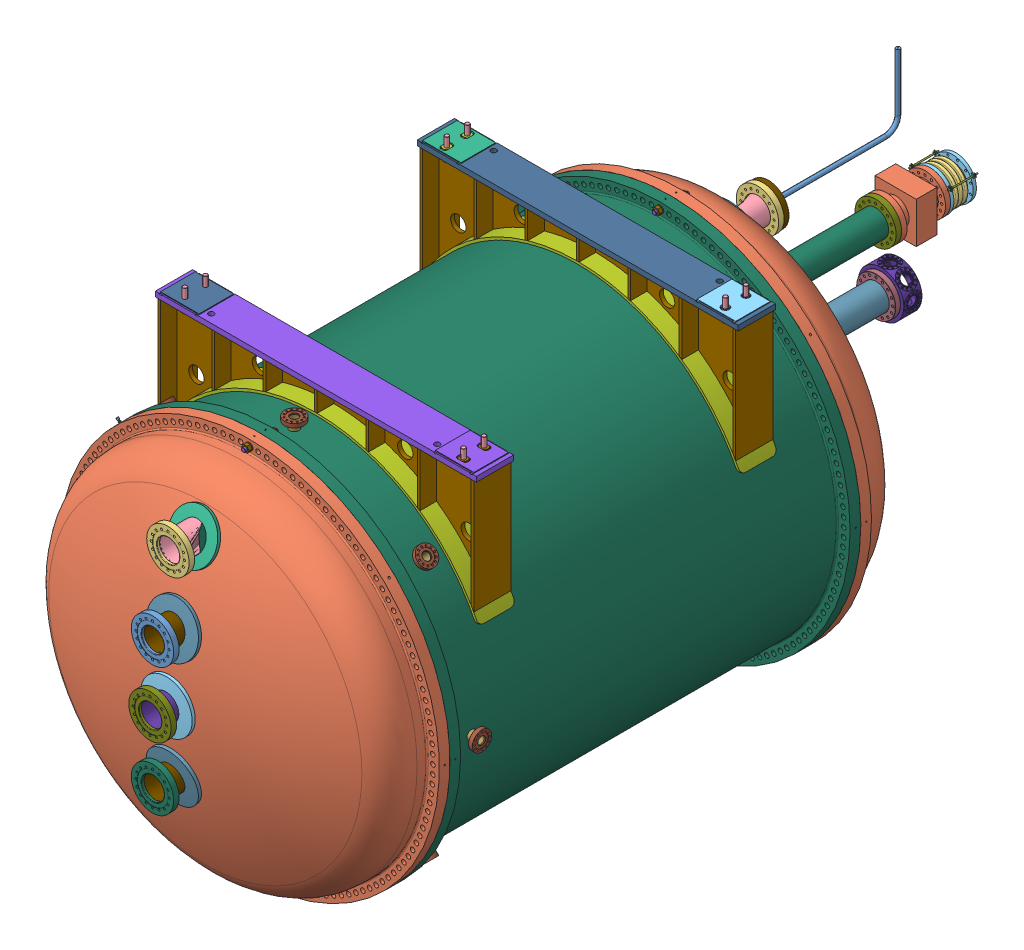
SolidWorks assembly pressure_vessel1_jordi, configuration Predeterminado. Lengths in mm.
Overall size (1480 1658.11 3261.35).
237 component instances, 64 part files, 0 mates.
Components (placement in the parent):
- mount_hardware-1: mount_hardware [Predeterminado] at (0 -3 0) size (1220 87.2 1155)
  - corner-free-1: corner-free [Predeterminado] at (-0.75 0 12.9) size (150 87 135)
    - key_free.1-1: key_free.1 [Predeterminado] at (0 0 -80) size (20 23.2 20)
    - key_free.1-2: key_free.1 [Predeterminado] at origin size (20 23.2 20)
    - fastener_set.1.1-1: fastener_set.1.1 [Predeterminado] at (0 0 -1040.4) size (50 87 50)
      - washer-1: washer [Predeterminado] at origin size (50 5 50)
      - m16-2_hhexnut-1: m16-2_hhexnut [Predeterminado] at (543.2477 766.8 336.1) size (24 16 27.71)
      - m16-stud-1: m16-stud [Predeterminado] at origin size (16 87 16)
    - fastener_set.1.1-2: fastener_set.1.1 [Predeterminado] at (0 0 -960.4) size (50 87 50)
      - washer-1: washer [Predeterminado] at origin size (50 5 50)
      - m16-2_hhexnut-1: m16-2_hhexnut [Predeterminado] at (543.2477 766.8 336.1) size (24 16 27.71)
      - m16-stud-1: m16-stud [Predeterminado] at origin size (16 87 16)
    - pad-free-1: pad-free [Predeterminado] at (1.4954 0 -288.2) x (-1 0 0) z (0 0 -1) size (150 6 135)
  - corner_hardware_long_slide-1: corner_hardware_long_slide [Predeterminado] at (0.7454 0 -275.3) x (-1 0 0) z (0 0 -1) size (150 87 135)
    - fastener_set.1.1-1: fastener_set.1.1 [Predeterminado] at (1086.4954 0 752.2) x (-1 0 0) z (0 0 -1) size (50 87 50)
      - washer-1: washer [Predeterminado] at origin size (50 5 50)
      - m16-2_hhexnut-1: m16-2_hhexnut [Predeterminado] at (543.2477 766.8 336.1) size (24 16 27.71)
      - m16-stud-1: m16-stud [Predeterminado] at origin size (16 87 16)
    - fastener_set.1.1-2: fastener_set.1.1 [Predeterminado] at (1086.4954 0 672.2) x (-1 0 0) z (0 0 -1) size (50 87 50)
      - washer-1: washer [Predeterminado] at origin size (50 5 50)
      - m16-2_hhexnut-1: m16-2_hhexnut [Predeterminado] at (543.2477 766.8 336.1) size (24 16 27.71)
      - m16-stud-1: m16-stud [Predeterminado] at origin size (16 87 16)
    - bearing_pad_1-1: bearing_pad_1 [Predeterminado] at origin size (150 6 135)
    - key.1-1: key.1 [Predeterminado] at origin size (26 23.2 30)
    - key.1-2: key.1 [Predeterminado] at (0 0 -80) size (26 23.2 30)
  - corner_hardware_transverse_slide-1: corner_hardware_transverse_slide [Predeterminado] at (-1 0 -8) size (149.75 87 135)
    - fastener_set.1.1-1: fastener_set.1.1 [Predeterminado] at (0 0 80) size (50 87 50)
      - washer-1: washer [Predeterminado] at origin size (50 5 50)
      - m16-2_hhexnut-1: m16-2_hhexnut [Predeterminado] at (543.2477 766.8 336.1) size (24 16 27.71)
      - m16-stud-1: m16-stud [Predeterminado] at origin size (16 87 16)
    - fastener_set.1.1-2: fastener_set.1.1 [Predeterminado] at origin size (50 87 50)
      - washer-1: washer [Predeterminado] at origin size (50 5 50)
      - m16-2_hhexnut-1: m16-2_hhexnut [Predeterminado] at (543.2477 766.8 336.1) size (24 16 27.71)
      - m16-stud-1: m16-stud [Predeterminado] at origin size (16 87 16)
    - bearing_pad-1: bearing_pad [Predeterminado] at origin size (149.75 6 135)
    - key-1: key [Predeterminado] at (127.1477 0 959.3477) x (0 0 -1) z (1 0 0) size (26 23.2 30)
    - key-2: key [Predeterminado] at (127.1477 0 879.3477) x (0 0 -1) z (1 0 0) size (26 23.2 30)
  - corner_fixed-1: corner_fixed [Predeterminado] at origin size (150 87 135)
    - fastener_set.1.1-1: fastener_set.1.1 [Predeterminado] at (-1085.75 0.2 72.5) size (50 87 50)
      - washer-1: washer [Predeterminado] at origin size (50 5 50)
      - m16-2_hhexnut-1: m16-2_hhexnut [Predeterminado] at (543.2477 766.8 336.1) size (24 16 27.71)
      - m16-stud-1: m16-stud [Predeterminado] at origin size (16 87 16)
    - fastener_set.1.1-2: fastener_set.1.1 [Predeterminado] at (-1085.75 0.2 -7.5) size (50 87 50)
      - washer-1: washer [Predeterminado] at origin size (50 5 50)
      - m16-2_hhexnut-1: m16-2_hhexnut [Predeterminado] at (543.2477 766.8 336.1) size (24 16 27.71)
      - m16-stud-1: m16-stud [Predeterminado] at origin size (16 87 16)
    - pad-fixed-1: pad-fixed [Predeterminado] at (-0.75 0 -7.5) size (150 6 135)
- tracking_head_assem_jordi-1: tracking_head_assem_jordi [Predeterminado] at (0 0 -17.4) x (-1 0 0) z (0 0 -1) size (1480 1510.05 550.83)
  - Hexagon_Socket_Head_Cap_Screw_5_16-18x1_255_ANSI_B18.3-1: Hexagon_Socket_Head_Cap_Screw_5_16-18x1_255_ANSI_B18.3 [Predeterminado] at (0 -660 -681.9) x (1 0 0) z (0 0 -1) size (11.91 11.91 39.8)
  - Hexagon_Socket_Head_Cap_Screw_5_16-18x1_255_ANSI_B18.3-2: Hexagon_Socket_Head_Cap_Screw_5_16-18x1_255_ANSI_B18.3 [Predeterminado] at (0 660 -681.5) x (-1 0 0) z (0 0 -1) size (11.91 11.91 39.8)
  - O-ring_press.1.1-1: O-ring_press.1.1 [Predeterminado] at (0 0 61.9) x (-1 0 0) z (0 0 -1) size (1377.4 1377.4 3.81)
  - O-ring_H2o-1: O-ring_H2o [Predeterminado] at (0 0 61.5) x (-1 0 0) z (0 0 -1) size (1392 1392 2.61)
  - head_weldment.1-1: head_weldment.1 [Predeterminado] at (0 0 -17.4) x (-1 0 0) z (0 0 -1) size (1480 1510.05 550.83)
    - reinforcement.axial.1.1.1-1: reinforcement.axial.1.1.1 [Predeterminado] at (0 -13.7355 -284.0742) x (1 0 0) z (0 0.183956 -0.982934) size (203.29 202.99 30.7)
    - nozzle_aux_l.2-1: nozzle_aux_l.2 [Predeterminado] at (0 0 -282.8) x (1 0 0) z (0 0 -1) size (165 165 21.44)
      - flange_aux_2-1: flange_aux_2 [Predeterminado] at (0 0 -69.4114) x (-1 0 0) z (0 0 -1) size (165 165 21.44)
    - nozzle_axial-1: nozzle_axial [Predeterminado] at (0 0 -282.8) x (-1 0 0) z (0 0 -1) size (165 165 85.73)
      - flange_1-1: flange_1 [Predeterminado] at (0 250 -79.4114) x (1 0 0) z (0 0 -1) size (165 165 21.44)
      - tube-1: tube [Predeterminado] at (0 0 -242.4894) size (101.6 101.6 74.63)
    - nozzle_aux_l-1: nozzle_aux_l [Predeterminado] at (0 0 -282.8) x (-1 0 0) z (0 0 -1) size (440 939.85 440)
      - nozzle_auxiliary.1-1: nozzle_auxiliary.1 [Predeterminado] at (0 -250 -242.8779) x (-1 0 0) z (0 0 1) size (440 440 440)
      - nozzle_auxiliary.1-2: nozzle_auxiliary.1 [Predeterminado] at (0 250 -242.8779) size (440 440 440)
      - flange_aux_1-1: flange_aux_1 [Predeterminado] at (0 0 -69.4114) x (-1 0 0) z (0 0 -1) size (165 165 21.44)
    - head_O_ring-1: head_O_ring [Predeterminado] at (0 0 -17.4) x (-1 0 0) z (0 0 -1) size (1480 1480 359.44)
    - nozzle_hv-1: nozzle_hv [Predeterminado] at (0 272.0886 -282.8) x (-1 0 0) z (0 0 -1) size (496.82 496.82 496.82)
      - flange_aux-1: flange_aux [Predeterminado] at (0 0 -9.4114) x (-1 0 0) z (0 0 -1) size (165 165 21.44)
      - nozzle_auxiliary-1: nozzle_auxiliary [Predeterminado] at (0 250 217.1221) size (496.82 496.82 496.82)
    - reinforcement.axial-1: reinforcement.axial [Predeterminado] at (0 0 -282.8) x (-1 0 0) z (0 0 -1) size (203.28 203.96 19.57)
    - reinforcement.axial.1.1.1-2: reinforcement.axial.1.1.1 [Predeterminado] at (0 13.7355 -284.0742) x (-1 0 0) z (0 -0.183956 -0.982934) size (203.29 202.99 30.7)
    - reinforcement.axial.1.2-1: reinforcement.axial.1.2 [Predeterminado] at (0 28.6873 -288.5308) x (-1 0 0) z (0 -0.384203 -0.923249) size (193.14 205.75 36.46)
- main_cyl_vessel-1: main_cyl_vessel [Predeterminado] at origin size (1480 1618.11 1626.05)
  - barrel_weldment.1-1: barrel_weldment.1 [Predeterminado] at origin size (1480 1537 1600)
    - support.1.1-1: support.1.1 [Predeterminado] at (0 0 882.5) size (1271.75 508.59 147.26)
      - pad-1: pad [Predeterminado] at (0 0 47.5) x (0.999999 0.001635 0) z (0 0 1) size (1271.08 410.55 147.26)
      - base_1-1: base_1 [Predeterminado] at (-0.75 27 0) size (1250 20 145)
      - plate.1-1: plate.1 [Predeterminado] at origin size (1230 442.67 145)
    - support.1-1: support.1 [Predeterminado] at (0 0 -137.5) size (1271.75 508.59 147.26)
      - base.1-1: base.1 [Predeterminado] at (0.7454 27 -1027.8) x (-1 0 0) z (0 0 -1) size (1250 20 145)
      - plate.1-1: plate.1 [Predeterminado] at origin size (1230 442.67 145)
      - pad-1: pad [Predeterminado] at (0 0 47.5) x (0.999999 0.001635 0) z (0 0 1) size (1271.08 410.55 147.26)
    - half_nipple_DN40_mdc_401002.3-1: half_nipple_DN40_mdc_401002.3 [Predeterminado] at (-504.8778 504.8778 525) x (-0.105943 -0.105943 -0.988712) z (-0.707107 0.707107 0) size (85.39 85.39 50.95)
      - flange_flat-1: flange_flat [Predeterminado] at (0 0 10.6864) x (0.988712 -0.149826 0) z (0 0 1) size (75 75 15)
      - tube_3-1: tube_3 [Predeterminado] at origin size (36 36 44.64)
    - half_nipple_DN40_mdc_401002.3-2: half_nipple_DN40_mdc_401002.3 [Predeterminado] at (-714.005 0 525) x (0 -0.149826 -0.988712) z (-1 0 0) size (85.39 85.39 50.95)
      - flange_flat-1: flange_flat [Predeterminado] at (0 0 10.6864) x (0.988712 -0.149826 0) z (0 0 1) size (75 75 15)
      - tube_3-1: tube_3 [Predeterminado] at origin size (36 36 44.64)
    - half_nipple_DN40_mdc_401002.3-3: half_nipple_DN40_mdc_401002.3 [Predeterminado] at (504.8778 -504.8778 525) x (0.105943 0.105943 -0.988712) z (0.707107 -0.707107 0) size (85.39 85.39 50.95)
      - flange_flat-1: flange_flat [Predeterminado] at (0 0 10.6864) x (0.988712 -0.149826 0) z (0 0 1) size (75 75 15)
      - tube_3-1: tube_3 [Predeterminado] at origin size (36 36 44.64)
    - half_nipple_DN40_mdc_401002.3-4: half_nipple_DN40_mdc_401002.3 [Predeterminado] at (714.005 0 525) x (0 0.149826 -0.988712) z (1 0 0) size (85.39 85.39 50.95)
      - flange_flat-1: flange_flat [Predeterminado] at (0 0 10.6864) x (0.988712 -0.149826 0) z (0 0 1) size (75 75 15)
      - tube_3-1: tube_3 [Predeterminado] at origin size (36 36 44.64)
    - half_nipple_DN40_mdc_401002.3-5: half_nipple_DN40_mdc_401002.3 [Predeterminado] at (504.8778 504.8778 525) x (-0.105943 0.105943 -0.988712) z (0.707107 0.707107 0) size (85.39 85.39 50.95)
      - flange_flat-1: flange_flat [Predeterminado] at (0 0 10.6864) x (0.988712 -0.149826 0) z (0 0 1) size (75 75 15)
      - tube_3-1: tube_3 [Predeterminado] at origin size (36 36 44.64)
    - half_nipple_DN40_mdc_401002.3-6: half_nipple_DN40_mdc_401002.3 [Predeterminado] at (0 714.005 525) x (-0.149826 0 -0.988712) z (0 1 0) size (85.39 85.39 50.95)
      - flange_flat-1: flange_flat [Predeterminado] at (0 0 10.6864) x (0.988712 -0.149826 0) z (0 0 1) size (75 75 15)
      - tube_3-1: tube_3 [Predeterminado] at origin size (36 36 44.64)
    - nozzle_DN75.1-1: nozzle_DN75.1 [Predeterminado] at (0 0 0.0857) x (0.707107 -0.707107 0) z (0 0 1) size (178.78 51.96 178.78)
      - tube_2-1: tube_2 [Predeterminado] at (0 -709.9952 516.5143) x (0.400618 0 -0.916245) z (0 -1 0) size (72 72 45.64)
      - flange_flat_DN75-1: flange_flat_DN75 [Predeterminado] at (0 -725.6914 516.5143) x (0.522753 0 -0.852484) z (0 -1 0) size (130 130 16.7)
    - nozzle_DN75.1-2: nozzle_DN75.1 [Predeterminado] at (0 0 0.0857) size (178.78 51.96 178.78)
      - tube_2-1: tube_2 [Predeterminado] at (0 -709.9952 516.5143) x (0.400618 0 -0.916245) z (0 -1 0) size (72 72 45.64)
      - flange_flat_DN75-1: flange_flat_DN75 [Predeterminado] at (0 -725.6914 516.5143) x (0.522753 0 -0.852484) z (0 -1 0) size (130 130 16.7)
    - main_vessel_bolt_flange_Oring-1: main_vessel_bolt_flange_Oring [Predeterminado] at (0 0 -140) size (1480 1480 1600)
  - half_nipple_DN40_mdc_401002.top-1: half_nipple_DN40_mdc_401002.top [Predeterminado] at (0 -729.005 516.6) x (0.400618 0 -0.916245) z (0 -1 0) size (261.68 261.68 242.65)
    - ft_CF75-1: ft_CF75 [Predeterminado] at (473.2537 -206.9251 -714.005) x (0.400618 0.916245 0) z (-0.916245 0.400618 0) size (198.72 242.65 198.72)
      - hv_feedthrough_assem-1: hv_feedthrough_assem [Predeterminado] at (45.0172 -129.75 1.9655) x (0.996195 0 0.087156) z (-0.087156 0 0.996195) size (183.43 242.65 183.43)
        - plunger-1: plunger [Predeterminado] at (0 73.6 0) size (7 109 7)
        - FT-vacom_50kV-1: FT-vacom_50kV [Predeterminado] at (-45.0172 110.4 1.9655) x (0.996195 0 -0.087156) z (0.087156 0 0.996195) size (94.08 221.5 94.08)
          - flange.1-1: flange.1 [Predeterminado] at (0 -744.3722 516.5143) x (-0.47895 0 0.877842) z (0 1 0) size (69.34 69.34 12.7)
          - insulator-1: insulator [Predeterminado] at (45.0172 -129.75 1.9655) x (0.996195 0 0.087156) z (-0.087156 0 0.996195) size (38.35 52 38.35)
          - conductor-1: conductor [Predeterminado] at (45.0172 -129.75 1.9655) x (0.996195 0 0.087156) z (-0.087156 0 0.996195) size (2 221.5 2)
        - DN75-40reducer3-1: DN75-40reducer3 [Predeterminado] at (0 -609.6136 516.5143) x (-0.222469 0 0.97494) z (0 1 0) size (130 130 19.05)
        - DN75_O-ring_adapter-1: DN75_O-ring_adapter [Predeterminado] at (0 -609.6136 516.5143) x (-0.753266 0 0.657716) z (0 -1 0) size (130 130 19.05)
  - pipe_tube5182K834-1: pipe_tube5182K834 [Predeterminado] at (-120.5041 -650.4585 -921.4) x (0.982918 -0.182173 0.026177) z (-0.182236 -0.983255 0) size (24.52 10 20.4)
    - p2_1-1: p2_1 [Predeterminado] at (-599.5111 15.6988 -1073.7738) x (-0.565333 0.04099 0.823844) z (-0.823844 0.021573 -0.566406) size (8.63 9.17 19.4)
    - p1_1-1: p1_1 [Predeterminado] at (-599.5111 15.6988 -1073.7738) x (-0.565333 0.04099 0.823844) z (-0.823844 0.021573 -0.566406) size (7.94 9.17 7.95)
  - pipe_tube5182K834-2: pipe_tube5182K834 [Predeterminado] at (-125.0832 -646.8042 679.3369) x (0.982918 -0.182173 0.026177) z (-0.182236 -0.983255 0) size (24.52 10 20.4)
    - p2_1-1: p2_1 [Predeterminado] at (-599.5111 15.6988 -1073.7738) x (-0.565333 0.04099 0.823844) z (-0.823844 0.021573 -0.566406) size (8.63 9.17 19.4)
    - p1_1-1: p1_1 [Predeterminado] at (-599.5111 15.6988 -1073.7738) x (-0.565333 0.04099 0.823844) z (-0.823844 0.021573 -0.566406) size (7.94 9.17 7.95)
  - SHOULDERBOLT_8XM6X10LG-1: SHOULDERBOLT_8XM6X10LG [Predeterminado] at (0 -670 649.6) x (0.949444 -0.313936 0) z (-0.313936 -0.949444 0) size (10 21.5 10)
- flange_bolts_16mm-1: flange_bolts_16mm [Predeterminado] at origin size (71.93 1467.41 1731.8)
  - fastener_set_16mm.2-1: fastener_set_16mm.2 [Predeterminado] at (-6.2049 -94.8144 -477.8) x (-0.998993 0.044865 0) z (0 0 -1) size (37.08 37.41 131)
    - washer_17id_28od_4t.1-1: washer_17id_28od_4t.1 [Predeterminado] at (0 -620 422.1) size (28 28 3)
    - washer_17id_28od_4t.1-2: washer_17id_28od_4t.1 [Predeterminado] at (0 -620 505.1) x (-1 0 0) z (0 0 -1) size (28 28 3)
    - stud_M16x1F.1-1: stud_M16x1F.1 [Predeterminado] at (-94.3992 -1323.6965 -306) x (-0.991122 0.132957 0) z (0 0 1) size (16 16 131)
    - nut_M16x1F.1-1: nut_M16x1F.1 [Predeterminado] at (-232.2561 -1194.854 -156.9) x (-0.927184 0.374607 0) z (0 0 1) size (25.63 27.47 13)
    - nut_M16x1F.1-2: nut_M16x1F.1 [Predeterminado] at (-379.8395 -1110.0224 1084.1) x (0.790359 -0.612644 0) z (0 0 -1) size (25.63 27.47 13)
  - fastener_set_16mm.2-2: fastener_set_16mm.2 [Predeterminado] at (0 95 -477.8) x (1 0 0) z (0 0 -1) size (37.08 37.41 131)
    - washer_17id_28od_4t.1-1: washer_17id_28od_4t.1 [Predeterminado] at (0 -620 422.1) size (28 28 3)
    - washer_17id_28od_4t.1-2: washer_17id_28od_4t.1 [Predeterminado] at (0 -620 505.1) x (-1 0 0) z (0 0 -1) size (28 28 3)
    - stud_M16x1F.1-1: stud_M16x1F.1 [Predeterminado] at (-94.3992 -1323.6965 -306) x (-0.991122 0.132957 0) z (0 0 1) size (16 16 131)
    - nut_M16x1F.1-1: nut_M16x1F.1 [Predeterminado] at (-232.2561 -1194.854 -156.9) x (-0.927184 0.374607 0) z (0 0 1) size (25.63 27.47 13)
    - nut_M16x1F.1-2: nut_M16x1F.1 [Predeterminado] at (-379.8395 -1110.0224 1084.1) x (0.790359 -0.612644 0) z (0 0 -1) size (25.63 27.47 13)
  - fastener_set_16mm.2-3: fastener_set_16mm.2 [Predeterminado] at (0 -95 -477.8) x (-1 0 0) z (0 0 -1) size (37.08 37.41 131)
    - washer_17id_28od_4t.1-1: washer_17id_28od_4t.1 [Predeterminado] at (0 -620 422.1) size (28 28 3)
    - washer_17id_28od_4t.1-2: washer_17id_28od_4t.1 [Predeterminado] at (0 -620 505.1) x (-1 0 0) z (0 0 -1) size (28 28 3)
    - stud_M16x1F.1-1: stud_M16x1F.1 [Predeterminado] at (-94.3992 -1323.6965 -306) x (-0.991122 0.132957 0) z (0 0 1) size (16 16 131)
    - nut_M16x1F.1-1: nut_M16x1F.1 [Predeterminado] at (-232.2561 -1194.854 -156.9) x (-0.927184 0.374607 0) z (0 0 1) size (25.63 27.47 13)
    - nut_M16x1F.1-2: nut_M16x1F.1 [Predeterminado] at (-379.8395 -1110.0224 1084.1) x (0.790359 -0.612644 0) z (0 0 -1) size (25.63 27.47 13)
  - fastener_set_16mm.2-4: fastener_set_16mm.2 [Predeterminado] at (0 95 195) x (-1 0 0) z (0 0 1) size (37.08 37.41 131)
    - washer_17id_28od_4t.1-1: washer_17id_28od_4t.1 [Predeterminado] at (0 -620 422.1) size (28 28 3)
    - washer_17id_28od_4t.1-2: washer_17id_28od_4t.1 [Predeterminado] at (0 -620 505.1) x (-1 0 0) z (0 0 -1) size (28 28 3)
    - stud_M16x1F.1-1: stud_M16x1F.1 [Predeterminado] at (-94.3992 -1323.6965 -306) x (-0.991122 0.132957 0) z (0 0 1) size (16 16 131)
    - nut_M16x1F.1-1: nut_M16x1F.1 [Predeterminado] at (-232.2561 -1194.854 -156.9) x (-0.927184 0.374607 0) z (0 0 1) size (25.63 27.47 13)
    - nut_M16x1F.1-2: nut_M16x1F.1 [Predeterminado] at (-379.8395 -1110.0224 1084.1) x (0.790359 -0.612644 0) z (0 0 -1) size (25.63 27.47 13)
  - fastener_set_16mm.2-5: fastener_set_16mm.2 [Predeterminado] at (0 -95 195) size (37.08 37.41 131)
    - washer_17id_28od_4t.1-1: washer_17id_28od_4t.1 [Predeterminado] at (0 -620 422.1) size (28 28 3)
    - washer_17id_28od_4t.1-2: washer_17id_28od_4t.1 [Predeterminado] at (0 -620 505.1) x (-1 0 0) z (0 0 -1) size (28 28 3)
    - stud_M16x1F.1-1: stud_M16x1F.1 [Predeterminado] at (-94.3992 -1323.6965 -306) x (-0.991122 0.132957 0) z (0 0 1) size (16 16 131)
    - nut_M16x1F.1-1: nut_M16x1F.1 [Predeterminado] at (-232.2561 -1194.854 -156.9) x (-0.927184 0.374607 0) z (0 0 1) size (25.63 27.47 13)
    - nut_M16x1F.1-2: nut_M16x1F.1 [Predeterminado] at (-379.8395 -1110.0224 1084.1) x (0.790359 -0.612644 0) z (0 0 -1) size (25.63 27.47 13)
- energy_head_assem_jordi-1: energy_head_assem_jordi [Predeterminado] at (0 0 -200.4) size (1480 1536.09 1251.86)
  - head_assem-1: head_assem [Predeterminado] at (0 0 200.4) size (1480 1536.09 1251.86)
    - NUT_m8-FT-1: NUT_m8-FT [Predeterminado] at (0 315.1256 -1334.0565) x (1 0 0) z (0 -1 0) size (13 6.97 15.01)
    - pin_retainer-1: pin_retainer [Predeterminado] at (38.5373 38.5373 -1) x (0.707107 -0.707107 0) z (0 0 1) size (1 13 1)
    - pin_retainer-2: pin_retainer [Predeterminado] at (38.5373 -38.5373 -1) x (-0.707107 -0.707107 0) z (0 0 1) size (1 13 1)
    - pin_retainer-3: pin_retainer [Predeterminado] at (-38.5373 -38.5373 -1) x (-0.707107 0.707107 0) z (0 0 1) size (1 13 1)
    - pin_retainer-4: pin_retainer [Predeterminado] at (-38.5373 38.5373 -1) x (0.707107 0.707107 0) z (0 0 1) size (1 13 1)
    - extension_nozzle_axial-1: extension_nozzle_axial [Predeterminado] at (0 0 -30) size (160 160 390)
      - flange_aux.1.1.1-1: flange_aux.1.1.1 [Predeterminado] at (0 250 -70.85) x (1 0 0) z (0 0 -1) size (160 160 21.44)
      - flange_CF_6in-1: flange_CF_6in [Predeterminado] at (0 0 -1730.1451) x (-1 0 0) z (0 0 -1) size (151.64 151.64 19.81)
      - tube_1-1: tube_1 [Predeterminado] at (0 0 -242.4894) size (101.85 101.85 368.46)
    - extension_nozzle_aux_l.1-1: extension_nozzle_aux_l.1 [Predeterminado] at (0 0 -30) size (160 160 400)
      - flange_aux.1.1.1-1: flange_aux.1.1.1 [Predeterminado] at (0 500 -60.85) x (1 0 0) z (0 0 -1) size (160 160 21.44)
      - nozzle_auxiliary_1-1: nozzle_auxiliary_1 [Predeterminado] at (0 250 -242.8779) size (101.85 101.85 378.46)
      - flange_aux_3-1: flange_aux_3 [Predeterminado] at (0 0 -439.4114) x (-1 0 0) z (0 0 -1) size (160 160 21.44)
    - O-ring_H2o-1: O-ring_H2o [Predeterminado] at (0 0 -203.9) x (0.998854 0.047854 0) z (0 0 -1) size (1392 1392 2.61)
    - O-ring_press.1.1-1: O-ring_press.1.1 [Predeterminado] at (0 0 -203.5) x (0.998854 0.047854 0) z (0 0 -1) size (1377.4 1377.4 3.81)
    - KIMBALL_OCTAGON_MCF600-SO200800-C-1: KIMBALL_OCTAGON_MCF600-SO200800-C [Predeterminado] at (0 0 -1795.4511) x (0 0 -1) z (1 0 0) size (190.37 186.76 190.37)
    - hv_feedthrough_assem.aux-1: hv_feedthrough_assem.aux [Predeterminado] at (0 522.0886 -179.1996) size (160 354 1025.39)
      - flange_aux.1-1: flange_aux.1 [Predeterminado] at (0 -250 148.3496) x (-1 0 0) z (0 0 -1) size (160 160 21.44)
      - tefzel-1: tefzel [Predeterminado] at (0 -250 149.1996) size (16.2 282.1 1025.39)
    - head_weldment.1-1: head_weldment.1 [Predeterminado] at (0 0 -282.8) x (-1 0 0) z (0 0 -1) size (1480 1510.05 550.83)
      - reinforcement.axial.1.1.1-1: reinforcement.axial.1.1.1 [Predeterminado] at (0 -13.7355 -284.0742) x (1 0 0) z (0 0.183956 -0.982934) size (203.29 202.99 30.7)
      - nozzle_aux_l.2-1: nozzle_aux_l.2 [Predeterminado] at (0 0 -282.8) x (1 0 0) z (0 0 -1) size (165 165 21.44)
        - flange_aux_2-1: flange_aux_2 [Predeterminado] at (0 0 -69.4114) x (-1 0 0) z (0 0 -1) size (165 165 21.44)
      - nozzle_axial-1: nozzle_axial [Predeterminado] at (0 0 -282.8) x (-1 0 0) z (0 0 -1) size (165 165 85.73)
        - flange_1-1: flange_1 [Predeterminado] at (0 250 -79.4114) x (1 0 0) z (0 0 -1) size (165 165 21.44)
        - tube-1: tube [Predeterminado] at (0 0 -242.4894) size (101.6 101.6 74.63)
      - nozzle_aux_l-1: nozzle_aux_l [Predeterminado] at (0 0 -282.8) x (-1 0 0) z (0 0 -1) size (440 939.85 440)
        - nozzle_auxiliary.1-1: nozzle_auxiliary.1 [Predeterminado] at (0 -250 -242.8779) x (-1 0 0) z (0 0 1) size (440 440 440)
        - nozzle_auxiliary.1-2: nozzle_auxiliary.1 [Predeterminado] at (0 250 -242.8779) size (440 440 440)
        - flange_aux_1-1: flange_aux_1 [Predeterminado] at (0 0 -69.4114) x (-1 0 0) z (0 0 -1) size (165 165 21.44)
      - head_O_ring-1: head_O_ring [Predeterminado] at (0 0 -17.4) x (-1 0 0) z (0 0 -1) size (1480 1480 359.44)
      - nozzle_hv-1: nozzle_hv [Predeterminado] at (0 272.0886 -282.8) x (-1 0 0) z (0 0 -1) size (496.82 496.82 496.82)
        - flange_aux-1: flange_aux [Predeterminado] at (0 0 -9.4114) x (-1 0 0) z (0 0 -1) size (165 165 21.44)
        - nozzle_auxiliary-1: nozzle_auxiliary [Predeterminado] at (0 250 217.1221) size (496.82 496.82 496.82)
      - reinforcement.axial-1: reinforcement.axial [Predeterminado] at (0 0 -282.8) x (-1 0 0) z (0 0 -1) size (203.28 203.96 19.57)
      - reinforcement.axial.1.1.1-2: reinforcement.axial.1.1.1 [Predeterminado] at (0 13.7355 -284.0742) x (-1 0 0) z (0 -0.183956 -0.982934) size (203.29 202.99 30.7)
      - reinforcement.axial.1.2-1: reinforcement.axial.1.2 [Predeterminado] at (0 28.6873 -288.5308) x (-1 0 0) z (0 -0.384203 -0.923249) size (193.14 205.75 36.46)
    - pr_valve-1: pr_valve [Predeterminado] at (0 500 -3050.8787) x (-1 0 0) z (0 0 1) size (160 160 191)
    - Expansion_joint_DN_300-24-1: Expansion_joint_DN_300-24 [Predeterminado] at (0 409.091 -2872.1834) x (0 0 -1) z (1 0 0) size (116.37 226.64 225.59)
      - Bellows_x_3-1: Bellows_x_3 [Predeterminado] at (-867.7643 -159.091 0) x (0 0 1) z (-1 0 0) size (152 152 98.91)
      - Skirt-1: Skirt [Predeterminado] at (-843.2202 -159.091 0) x (0 0 -1) z (-1 0 0) size (150.73 123.2 81.91)
      - Flange_with_bracket-1: Flange_with_bracket [Predeterminado] at origin size (12.82 174.55 171.94)
        - Flange-1: Flange [Predeterminado] at (-921.0383 -159.091 0) size (12.82 160 160)
        - Bracket.2-1: Bracket.2 [Predeterminado] at (-916.6747 -239.0909 0) x (0 0 -1) z (0 -1 0) size (16.36 1.45 14.55)
        - Bracket.2-2: Bracket.2 [Predeterminado] at (-915.2201 -119.091 -69.282) x (0 -0.866025 -0.5) z (0 0.5 -0.866025) size (16.36 1.45 14.55)
        - Bracket.2-3: Bracket.2 [Predeterminado] at (-915.2201 -119.091 69.282) x (0 0.866025 -0.5) z (0 0.5 0.866025) size (16.36 1.45 14.55)
      - Flange_with_bracket-2: Flange_with_bracket [Predeterminado] at (-1741.7131 -238.6365 -137.7768) x (-1 0 0) z (0 -0.866025 0.5) size (12.82 174.55 171.94)
        - Flange-1: Flange [Predeterminado] at (-921.0383 -159.091 0) size (12.82 160 160)
        - Bracket.2-1: Bracket.2 [Predeterminado] at (-916.6747 -239.0909 0) x (0 0 -1) z (0 -1 0) size (16.36 1.45 14.55)
        - Bracket.2-2: Bracket.2 [Predeterminado] at (-915.2201 -119.091 -69.282) x (0 -0.866025 -0.5) z (0 0.5 -0.866025) size (16.36 1.45 14.55)
        - Bracket.2-3: Bracket.2 [Predeterminado] at (-915.2201 -119.091 69.282) x (0 0.866025 -0.5) z (0 0.5 0.866025) size (16.36 1.45 14.55)
      - Fixation_bolt.2-1: Fixation_bolt.2 [Predeterminado] at (300 -240 0) x (0 0 -1) z (0 1 0) size (8.73 116.37 8.73)
        - Pin_bolt-1: Pin_bolt [Predeterminado] at (0 1111.9475 -6.3636) size (4.37 116.37 4.37)
        - Flat_washer_12_mm.3-1: Flat_washer_12_mm.3 [Predeterminado] at (0 1125.0384 -6.3636) x (0 0 -1) z (0 1 0) size (8.73 8.73 0.91)
        - Flat_washer_12_mm.3-2: Flat_washer_12_mm.3 [Predeterminado] at (0 1122.6748 -6.3636) x (0 0 1) z (0 1 0) size (8.73 8.73 0.91)
        - Flat_washer_12_mm.3-3: Flat_washer_12_mm.3 [Predeterminado] at (0 1215.2201 -6.3636) x (0 0 -1) z (0 -1 0) size (8.73 8.73 0.91)
        - Flat_washer_12_mm.3-4: Flat_washer_12_mm.3 [Predeterminado] at (0 1217.5838 -6.3636) x (0 0 -1) z (0 -1 0) size (8.73 8.73 0.91)
        - Flat_nut_M12.2-1: Flat_nut_M12.2 [Predeterminado] at (0 1125.9475 -6.3636) x (0 -1 0) z (0 0 1) size (2.64 6.55 8.08)
        - Flat_nut_M12.2-2: Flat_nut_M12.2 [Predeterminado] at (0 1122.6748 -6.3636) x (0 1 0) z (0 0 1) size (2.64 6.55 8.08)
        - Flat_nut_M12.2-3: Flat_nut_M12.2 [Predeterminado] at (0 1214.311 -6.3636) x (0 1 0) z (0 0 1) size (2.64 6.55 8.08)
        - Flat_nut_M12.2-4: Flat_nut_M12.2 [Predeterminado] at (0 1217.5838 -6.3636) x (0 -1 0) z (0 0 1) size (2.64 6.55 8.08)
      - Fixation_bolt.2-2: Fixation_bolt.2 [Predeterminado] at (300 -118.6365 -70.0692) x (0 0.866025 0.5) z (0 -0.5 0.866025) size (8.73 116.37 8.73)
        - Pin_bolt-1: Pin_bolt [Predeterminado] at (0 1111.9475 -6.3636) size (4.37 116.37 4.37)
        - Flat_washer_12_mm.3-1: Flat_washer_12_mm.3 [Predeterminado] at (0 1125.0384 -6.3636) x (0 0 -1) z (0 1 0) size (8.73 8.73 0.91)
        - Flat_washer_12_mm.3-2: Flat_washer_12_mm.3 [Predeterminado] at (0 1122.6748 -6.3636) x (0 0 1) z (0 1 0) size (8.73 8.73 0.91)
        - Flat_washer_12_mm.3-3: Flat_washer_12_mm.3 [Predeterminado] at (0 1215.2201 -6.3636) x (0 0 -1) z (0 -1 0) size (8.73 8.73 0.91)
        - Flat_washer_12_mm.3-4: Flat_washer_12_mm.3 [Predeterminado] at (0 1217.5838 -6.3636) x (0 0 -1) z (0 -1 0) size (8.73 8.73 0.91)
        - Flat_nut_M12.2-1: Flat_nut_M12.2 [Predeterminado] at (0 1125.9475 -6.3636) x (0 -1 0) z (0 0 1) size (2.64 6.55 8.08)
        - Flat_nut_M12.2-2: Flat_nut_M12.2 [Predeterminado] at (0 1122.6748 -6.3636) x (0 1 0) z (0 0 1) size (2.64 6.55 8.08)
        - Flat_nut_M12.2-3: Flat_nut_M12.2 [Predeterminado] at (0 1214.311 -6.3636) x (0 1 0) z (0 0 1) size (2.64 6.55 8.08)
        - Flat_nut_M12.2-4: Flat_nut_M12.2 [Predeterminado] at (0 1217.5838 -6.3636) x (0 -1 0) z (0 0 1) size (2.64 6.55 8.08)
      - Fixation_bolt.2-3: Fixation_bolt.2 [Predeterminado] at (300 -110.4258 79.4798) x (0 0.612776 -0.790257) z (0 0.790257 0.612776) size (8.73 116.37 8.73)
        - Pin_bolt-1: Pin_bolt [Predeterminado] at (0 1111.9475 -6.3636) size (4.37 116.37 4.37)
        - Flat_washer_12_mm.3-1: Flat_washer_12_mm.3 [Predeterminado] at (0 1125.0384 -6.3636) x (0 0 -1) z (0 1 0) size (8.73 8.73 0.91)
        - Flat_washer_12_mm.3-2: Flat_washer_12_mm.3 [Predeterminado] at (0 1122.6748 -6.3636) x (0 0 1) z (0 1 0) size (8.73 8.73 0.91)
        - Flat_washer_12_mm.3-3: Flat_washer_12_mm.3 [Predeterminado] at (0 1215.2201 -6.3636) x (0 0 -1) z (0 -1 0) size (8.73 8.73 0.91)
        - Flat_washer_12_mm.3-4: Flat_washer_12_mm.3 [Predeterminado] at (0 1217.5838 -6.3636) x (0 0 -1) z (0 -1 0) size (8.73 8.73 0.91)
        - Flat_nut_M12.2-1: Flat_nut_M12.2 [Predeterminado] at (0 1125.9475 -6.3636) x (0 -1 0) z (0 0 1) size (2.64 6.55 8.08)
        - Flat_nut_M12.2-2: Flat_nut_M12.2 [Predeterminado] at (0 1122.6748 -6.3636) x (0 1 0) z (0 0 1) size (2.64 6.55 8.08)
        - Flat_nut_M12.2-3: Flat_nut_M12.2 [Predeterminado] at (0 1214.311 -6.3636) x (0 1 0) z (0 0 1) size (2.64 6.55 8.08)
        - Flat_nut_M12.2-4: Flat_nut_M12.2 [Predeterminado] at (0 1217.5838 -6.3636) x (0 -1 0) z (0 0 1) size (2.64 6.55 8.08)
    - shield_head-1: shield_head [Predeterminado] at origin size (1342.71 1394.62 471.89)
